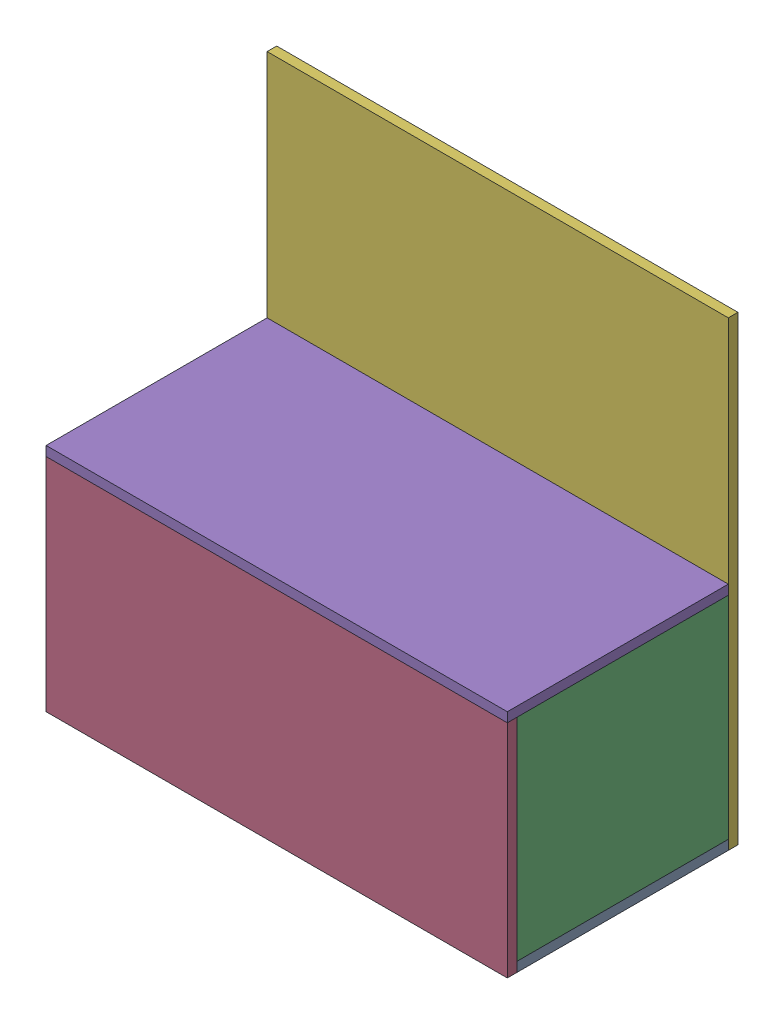
SolidWorks assembly big_box_assem2, configuration Default. Lengths in mm.
Overall size (609.6 609.6 292.1).
7 component instances, 5 part files, 3 mates.
Components (placement in the parent):
- Assem1^big_box_assem2-1: Assem1^big_box_assem2 [Default] at origin size (609.6 609.6 304.8) (virtual)
  - bottom_plate-1: bottom_plate [Default] at (0 0 279.4) x (1 0 0) z (0 1 0) size (609.6 279.4 12.7)
  - side_panel-1: side_panel [Default] at (0 12.7 279.4) x (0 0 -1) z (1 0 0) size (279.4 279.4 12.7)
  - side_panel-2: side_panel [Default] at (609.6 12.7 0) x (0 0 1) z (-1 0 0) size (279.4 279.4 12.7)
  - front_panel-1: front_panel [Default] at (0 0 279.4) size (609.6 292.1 12.7) (hidden)
  - top_panel-1: top_panel [Default] at (0 292.1 292.1) x (1 0 0) z (0 1 0) size (609.6 292.1 12.7) (hidden)
  - back_plate-1: back_plate [Default] at (0 0 -12.7) size (609.6 609.6 12.7)
Mates (geometry in assembly coordinates):
- Coincident26: coincident aligned: plane of Assem1^big_box_assem-1/back_plate-1 through (0 0 0) normal (0 0 1)
- Coincident27: coincident anti-aligned: plane of Assem1^big_box_assem-1/back_plate-1 through (0 0 0) normal (0 -1 0)
- Coincident28: coincident anti-aligned: plane of Assem1^big_box_assem-1/back_plate-1 through (0 0 0) normal (-1 0 0)
